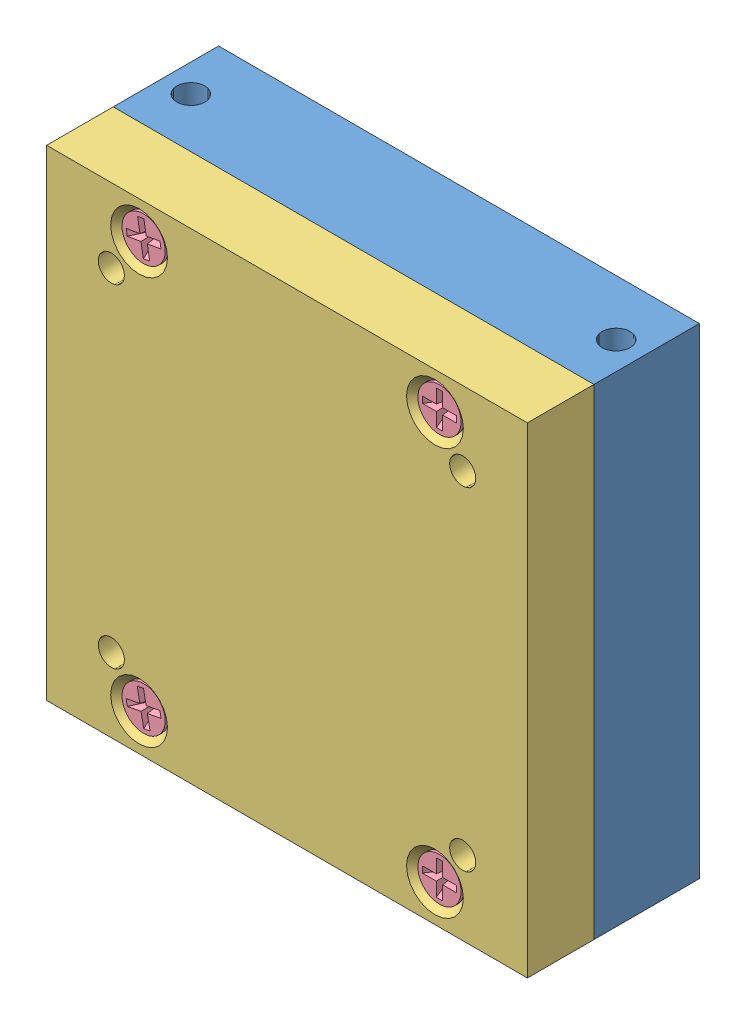
SolidWorks assembly Magnet Assembly, configuration Default. Lengths in mm.
Overall size (82.55 82.55 29.53).
7 component instances, 4 part files, 13 mates.
Components (placement in the parent):
- magnet holder-1: magnet holder [Default] at (-7.3988 1.6617 -6.7497) size (82.55 82.55 18.1)
- Magnet 31-1: Magnet 31 [Default] at (-7.3988 1.6617 -5.1622) x (0.999112 -0.042142 0) z (0 0 1) size (76.2 76.2 25.4)
- magnet plate-1: magnet plate [Default] at (-7.3988 1.6617 11.3478) size (82.55 82.55 11.43)
- CR-FHMS 0.164-32x1x1-N-1: CR-FHMS 0.164-32x1x1-N [CR-FHMS 0.164-32x1x1-N] at (-32.7988 36.5867 21.9997) x (0 0 -1) z (-0.169258 0.985572 0) size (25.4 7.42 7.42)
- CR-FHMS 0.164-32x1x1-N-5: CR-FHMS 0.164-32x1x1-N [CR-FHMS 0.164-32x1x1-N] at (-32.7988 -33.2633 21.9997) x (0 0 -1) z (0.981591 0.190995 0) size (25.4 7.42 7.42)
- CR-FHMS 0.164-32x1x1-N-6: CR-FHMS 0.164-32x1x1-N [CR-FHMS 0.164-32x1x1-N] at (18.0012 -33.2633 21.9997) x (0 0 -1) z (1 0 0) size (25.4 7.42 7.42)
- CR-FHMS 0.164-32x1x1-N-7: CR-FHMS 0.164-32x1x1-N [CR-FHMS 0.164-32x1x1-N] at (18.0012 36.5867 21.9997) x (0 0 -1) z (1 0 0) size (25.4 7.42 7.42)
Mates (geometry in assembly coordinates):
- Concentric1: concentric anti-aligned: cylinder of magnet holder-1 through (-7.3988 1.6617 -5.1622) axis (0 0 1) radius 38.1; cylinder of Magnet 31-1 through (-7.3988 1.6617 20.2378) axis (0 0 -1) radius 38.1
- Coincident1: coincident anti-aligned: plane of magnet holder-1 through (-7.3988 1.6617 -5.1622) normal (0 0 1); plane of Magnet 31-1 through (-7.3988 1.6617 -5.1622) normal (0 0 -1)
- Concentric2: concentric aligned: cylinder of Magnet 31-1 through (-7.3988 1.6617 20.2378) axis (0 0 -1) radius 38.1; cylinder of magnet plate-1 through (-7.3988 1.6617 20.2378) axis (0 0 -1) radius 38.1
- Parallel1: parallel aligned: plane of magnet holder-1 through (33.8762 42.9367 11.3478) normal (0 1 0); plane of magnet plate-1 through (33.8762 42.9367 22.7778) normal (0 1 0)
- Coincident3: coincident anti-aligned: plane of Magnet 31-1 through (-7.3988 1.6617 20.2378) normal (0 0 1); plane of magnet plate-1 through (-7.3988 1.6617 20.2378) normal (0 0 -1)
- Concentric3: concentric aligned: cylinder of magnet plate-1 through (-32.7988 36.5867 22.7778) axis (0 0 1) radius 2.2479; cylinder of CR-FHMS 0.164-32x1x1-N-1 through (-32.7988 36.5867 28.3497) axis (0 0 1) radius 2.0828
- Coincident4: coincident aligned: cone of magnet plate-1 through (-32.7988 36.5867 22.7778) axis (0 0 -1); cone of CR-FHMS 0.164-32x1x1-N-1 through (-32.7988 36.5867 21.4314) axis (0 0 -1)
- Concentric4: concentric aligned: cylinder of magnet plate-1 through (-32.7988 -33.2633 22.7778) axis (0 0 1) radius 2.2479; cylinder of CR-FHMS 0.164-32x1x1-N-5 through (-32.7988 -33.2633 28.3497) axis (0 0 1) radius 2.0828
- Concentric5: concentric aligned: cylinder of magnet plate-1 through (18.0012 -33.2633 22.7778) axis (0 0 1) radius 2.2479; cylinder of CR-FHMS 0.164-32x1x1-N-6 through (18.0012 -33.2633 28.3497) axis (0 0 1) radius 2.0828
- Concentric6: concentric aligned: cylinder of magnet plate-1 through (18.0012 36.5867 22.7778) axis (0 0 1) radius 2.2479; cylinder of CR-FHMS 0.164-32x1x1-N-7 through (18.0012 36.5867 28.3497) axis (0 0 1) radius 2.0828
- Coincident5: coincident aligned: cone of magnet plate-1 through (18.0012 -33.2633 22.7778) axis (0 0 -1); cone of CR-FHMS 0.164-32x1x1-N-6 through (18.0012 -33.2633 21.4314) axis (0 0 -1)
- Coincident6: coincident aligned: cone of magnet plate-1 through (18.0012 36.5867 22.7778) axis (0 0 -1); cone of CR-FHMS 0.164-32x1x1-N-7 through (18.0012 36.5867 21.4314) axis (0 0 -1)
- Coincident7: coincident aligned: cone of magnet plate-1 through (-32.7988 -33.2633 22.7778) axis (0 0 -1); cone of CR-FHMS 0.164-32x1x1-N-5 through (-32.7988 -33.2633 21.4314) axis (0 0 -1)
